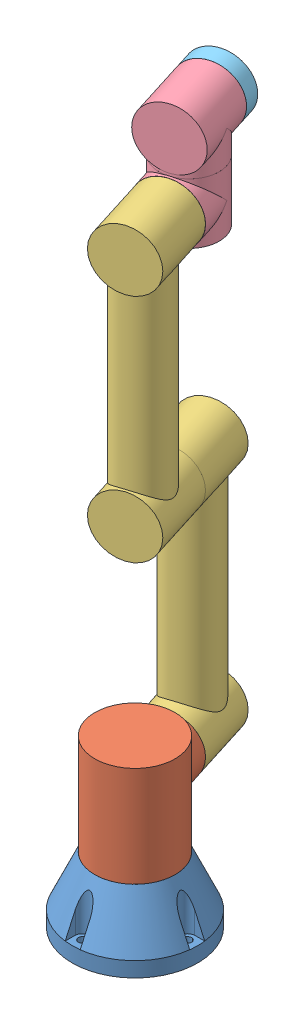
SolidWorks assembly armProto, configuration Default. Lengths in mm.
Overall size (132.71 680.4 195.91).
7 component instances, 5 part files, 17 mates.
Components (placement in the parent):
- armBase-1: armBase [Default] at origin size (125 80 125)
- armLink1-1: armLink1 [Default] at (0 65 0) x (-0.954 0 0.299808) z (-0.299808 0 -0.954) size (80 100 105)
- armLink2-1: armLink2 [Default] at (-26.2332 125 -83.475) x (0 1 0) z (0.299808 0 0.954) size (290 60 80)
- armLink2-2: armLink2 [Default] at (-3.7476 355 -11.925) x (0 1 0) z (-0.299808 0 -0.954) size (290 60 80)
- armLink3-1: armLink3 [Default] at (-24.7341 585 -78.705) x (0.954 0 -0.299808) z (0 -1 0) size (60 62.5 75)
- armLink3-2: armLink3 [Default] at (-24.7341 647.5 -78.705) x (-0.954 0 0.299808) z (0.299808 0 0.954) size (60 62.5 75)
- armEFMount-1: armEFMount [Default] at (-33.7283 647.5 -107.325) x (-0.94904 0.101838 0.298249) z (-0.299808 0 -0.954) size (60 60 17)
Mates (geometry in assembly coordinates):
- Coincident3: coordinate: point of armBase-1
- Concentric1: concentric anti-aligned: cylinder of armBase-1 through (0 65 0) axis (0 1 0) radius 15; cylinder of armLink1-1 through (0 80 0) axis (0 -1 0) radius 15
- Coincident4: coincident anti-aligned: plane of armBase-1 through (40 65 0) normal (0 1 0); plane of armLink1-1 through (0 65 0) normal (0 -1 0)
- Coincident5: coincident anti-aligned: plane of armLink1-1 through (-14.9904 65 -47.7) normal (-0.299808 0 -0.954); plane of armLink2-1 through (-14.9904 125 -47.7) normal (0.299808 0 0.954)
- Concentric2: concentric aligned: cylinder of armLink1-1 through (-19.4875 125 -62.01) axis (0.299808 0 0.954) radius 15; cylinder of armLink2-1 through (-19.4875 125 -62.01) axis (0.299808 0 0.954) radius 15
- Coincident6: coincident anti-aligned: plane of armLink2-1 through (-14.9904 125 -47.7) normal (0.299808 0 0.954); plane of armLink2-2 through (-14.9904 355 -47.7) normal (-0.299808 0 -0.954)
- Concentric3: concentric aligned: cylinder of armLink2-1 through (-10.4933 355 -33.39) axis (-0.299808 0 -0.954) radius 15; cylinder of armLink2-2 through (-10.4933 355 -33.39) axis (-0.299808 0 -0.954) radius 15
- Coincident7: coincident anti-aligned: plane of armLink2-2 through (-14.9904 355 -47.7) normal (-0.299808 0 -0.954); plane of armLink3-1 through (-14.9904 585 -47.7) normal (0.299808 0 0.954)
- Concentric4: concentric aligned: cylinder of armLink2-2 through (-19.4875 585 -62.01) axis (0.299808 0 0.954) radius 15; cylinder of armLink3-1 through (-19.4875 585 -62.01) axis (0.299808 0 0.954) radius 15
- Coincident8: coincident anti-aligned: plane of armLink3-1 through (-24.7341 615 -78.705) normal (0 1 0); plane of armLink3-2 through (-24.7341 615 -78.705) normal (0 -1 0)
- Concentric5: concentric aligned: cylinder of armLink3-1 through (-24.7341 630 -78.705) axis (0 -1 0) radius 15; cylinder of armLink3-2 through (-24.7341 630 -78.705) axis (0 -1 0) radius 15
- Concentric6: concentric aligned: cylinder of armLink3-2 through (-38.2255 647.5 -121.635) axis (0.299808 0 0.954) radius 15; cylinder of armEFMount-1 through (-38.2255 647.5 -121.635) axis (0.299808 0 0.954) radius 15
- Coincident9: coincident anti-aligned: plane of armLink3-2 through (-33.7283 647.5 -107.325) normal (-0.299808 0 -0.954); plane of armEFMount-1 through (-33.7283 647.5 -107.325) normal (0.299808 0 0.954)
- Parallel1: parallel aligned: line of armLink2-1 through (-34.4779 125 -109.71) axis (0 1 0); line of armLink2-2 through (4.4971 355 14.31) axis (0 1 0)
- Parallel2: parallel anti-aligned: plane of armLink1-1 through (0 165 0) normal (0 1 0); plane of armLink3-1 through (-24.7341 555 -78.705) normal (0 -1 0)
- Perpendicular1: perpendicular: plane of armLink1-1 through (0 165 0) normal (0 1 0); line of armLink2-1 through (-34.4779 125 -109.71) axis (0 1 0)
- Parallel4: parallel aligned: plane of armLink2-1 through (-34.4779 125 -109.71) normal (-0.299808 0 -0.954); plane of armEFMount-1 through (-38.8251 647.5 -123.543) normal (-0.299808 0 -0.954)
